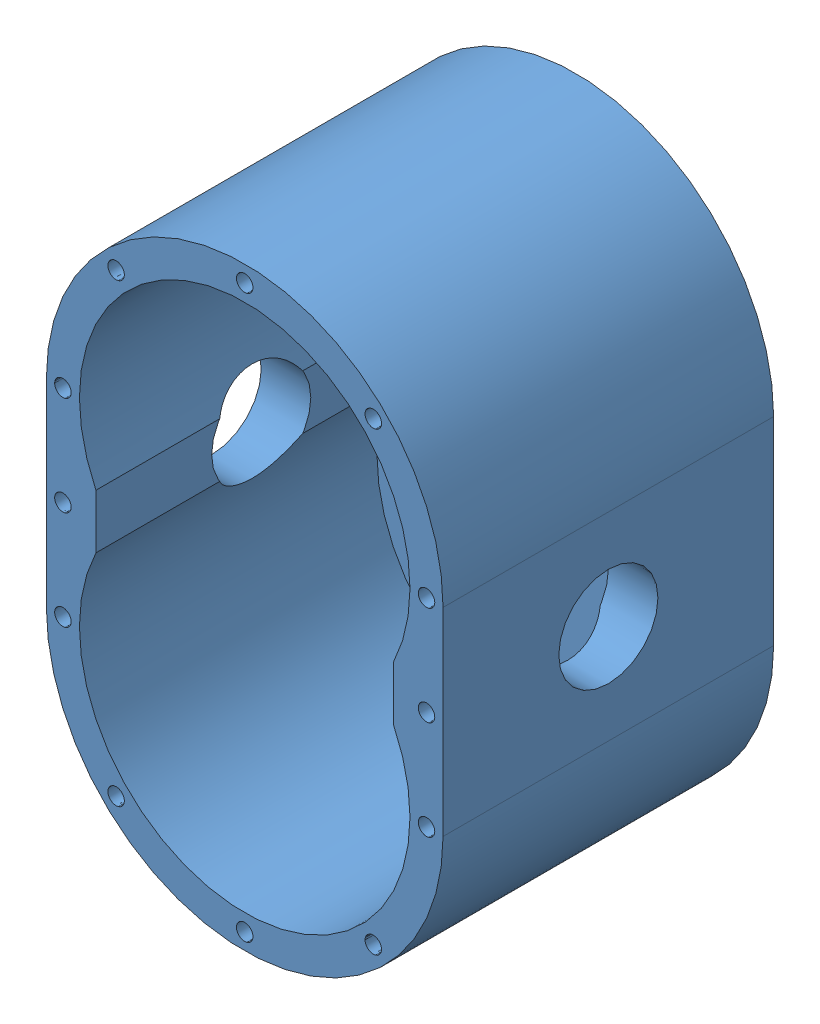
SolidWorks assembly 01-20-A-000-R00 Pneumatics, configuration Default. Lengths in mm.
Overall size (120 180 100).
2 component instances, 1 part files, 3 mates.
Components (placement in the parent):
- 01-21-A-000-R00 Lobe Compressor Assembly-1: 01-21-A-000-R00 Lobe Compressor Assembly [Default] at origin size (120 180 100)
  - 01-21-P-001-R00 Compressor Housing-1: 01-21-P-001-R00 Compressor Housing [Default] at origin size (120 180 100)
Mates (geometry in assembly coordinates):
- Coincident2: coincident: plane of 01-21-A-000-R00 Lobe Compressor Assembly-1/01-21-P-001-R00 Compressor Housing-1 through (0 0 0) normal (0 1 0)
- Coincident3: coincident: plane of 01-21-A-000-R00 Lobe Compressor Assembly-1/01-21-P-001-R00 Compressor Housing-1 through (0 0 0) normal (1 0 0)
- Coincident4: coincident aligned: plane of 01-21-A-000-R00 Lobe Compressor Assembly-1/01-21-P-001-R00 Compressor Housing-1 through (0 0 0) normal (0 0 1)
